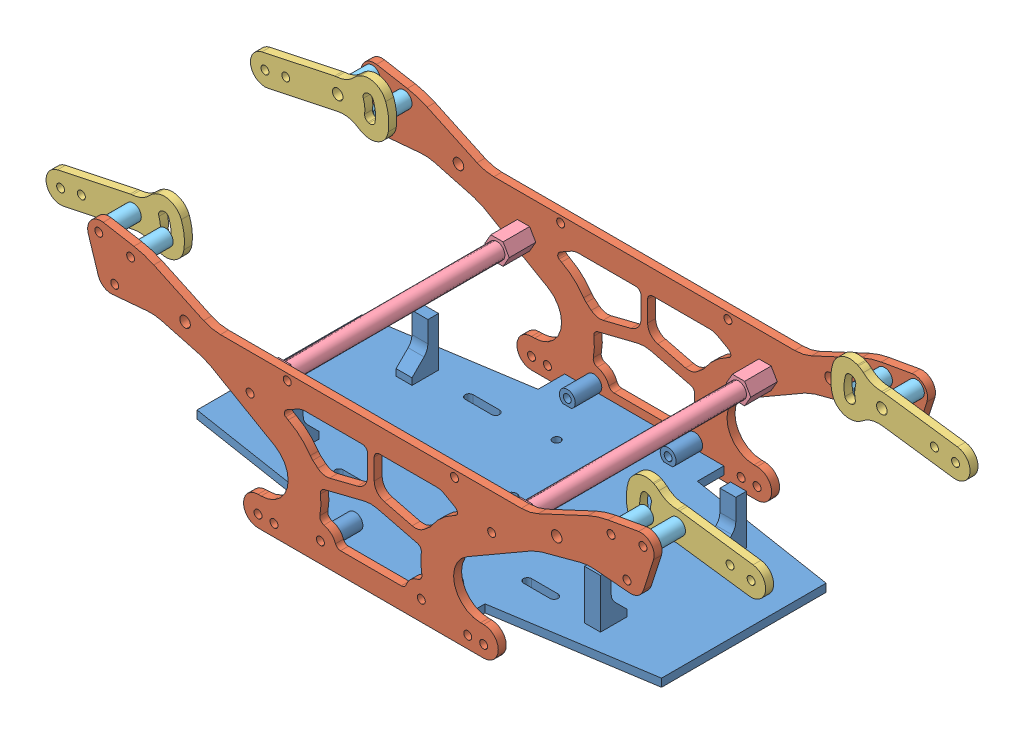
SolidWorks assembly Core, configuration Default. Lengths in mm.
Overall size (273.89 78.88 106.01).
17 component instances, 5 part files, 38 mates.
Components (placement in the parent):
- Chassis_2-1: Chassis_2 [Default] at origin size (175 21.5 100)
- Chassis_1-1: Chassis_1 [Default] at (0 -2 53) x (0 0 -1) z (1 0 0) size (3.01 70.64 213.45)
- Chassis_1-2: Chassis_1 [Default] at (0 -2 -50) x (0 0 -1) z (1 0 0) size (3.01 70.64 213.45)
- Chassis_3-1: Chassis_3 [Default] at (130.2491 60.7601 40) x (0 0 -1) z (0.99104 -0.133567 0) size (3 19.67 52.75)
- Chassis_3-2: Chassis_3 [Default] at (130.2491 60.7601 -37) x (0 0 -1) z (0.99104 -0.133567 0) size (3 19.67 52.75)
- Chassis_3-3: Chassis_3 [Default] at (-129.8911 58.6926 -40) x (0 0 1) z (-0.978254 -0.207408 0) size (3 19.67 52.75)
- Chassis_3-4: Chassis_3 [Default] at (-129.8911 58.6926 37) x (0 0 1) z (-0.978254 -0.207408 0) size (3 19.67 52.75)
- Chassis_4-1: Chassis_4 [Default] at (45.5 40.5 -50) size (9.24 8 100)
- Chassis_4-2: Chassis_4 [Default] at (-45.5 40.5 -50) size (9.24 8 100)
- Chassis_5-1: Chassis_5 [Default] at (90.5 62.3841 40) size (6 6 10)
- Chassis_5-2: Chassis_5 [Default] at (-102.5 64.5 -50) size (6 6 10)
- Chassis_5-3: Chassis_5 [Default] at (-102.5 64.5 40) size (6 6 10)
- Chassis_5-4: Chassis_5 [Default] at (90.5 62.3841 -50) size (6 6 10)
- Chassis_5-5: Chassis_5 [Default] at (102.5 64.5 -50) size (6 6 10)
- Chassis_5-6: Chassis_5 [Default] at (-90.5 62.3841 40) x (0.998337 0.057643 0) z (0 0 1) size (6 6 10)
- Chassis_5-7: Chassis_5 [Default] at (102.5 64.5 40) x (0.975239 -0.221151 0) z (0 0 1) size (6 6 10)
- Chassis_5-8: Chassis_5 [Default] at (-90.5 62.3841 -50) size (6 6 10)
Mates (geometry in assembly coordinates):
- Coincident1: coincident anti-aligned: plane of Chassis_2-1 through (0 3 50) normal (0 0 1); plane of Chassis_1-1 through (0 -2 50) normal (0 0 -1)
- Concentric1: concentric aligned: cylinder of Chassis_2-1 through (19 5.5 40) axis (0 0 1) radius 1.5; cylinder of Chassis_1-1 through (19 5.5 50) axis (0 0 1) radius 1.5
- Concentric2: concentric aligned: cylinder of Chassis_2-1 through (-19 5.5 40) axis (0 0 1) radius 1.5; cylinder of Chassis_1-1 through (-19 5.5 50) axis (0 0 1) radius 1.5
- Coincident2: coincident anti-aligned: plane of Chassis_2-1 through (0 3 -50) normal (0 0 -1); plane of Chassis_1-2 through (0 -2 -50) normal (0 0 1)
- Concentric3: concentric anti-aligned: cylinder of Chassis_2-1 through (-19 5.5 -40) axis (0 0 -1) radius 1.5; cylinder of Chassis_1-2 through (-19 5.5 -53) axis (0 0 1) radius 1.5
- Concentric4: concentric anti-aligned: cylinder of Chassis_2-1 through (19 5.5 -40) axis (0 0 -1) radius 1.5; cylinder of Chassis_1-2 through (19 5.5 -53) axis (0 0 1) radius 1.5
- Concentric5: concentric aligned: circle of Chassis_1-1; cylinder of Chassis_3-1 through (102.5 64.5 37) axis (0 0 1) radius 2
- Distance1: distance = 10 mm anti-aligned: plane of Chassis_3-1 through (130.2491 60.7601 40) normal (0 0 1); plane of Chassis_1-1 through (0 -2 50) normal (0 0 -1)
- Concentric6: concentric aligned: cylinder of Chassis_1-2 through (102.5 64.5 -53) axis (0 0 1) radius 1.5; cylinder of Chassis_3-2 through (102.5 64.5 -40) axis (0 0 1) radius 2
- Distance2: distance = 10 mm anti-aligned: plane of Chassis_3-2 through (130.2491 60.7601 -40) normal (0 0 -1); plane of Chassis_1-2 through (0 -2 -50) normal (0 0 1)
- Parallel1: parallel aligned: plane of Chassis_3-1 through (130.9837 66.2108 37) normal (0.133567 0.99104 0); plane of Chassis_3-2 through (130.9837 66.2108 -40) normal (0.133567 0.99104 0)
- Concentric7: concentric anti-aligned: cylinder of Chassis_1-2 through (-102.5 64.5 -53) axis (0 0 1) radius 1.5; cylinder of Chassis_3-3 through (-102.5 64.5 -37) axis (0 0 -1) radius 2
- Distance3: distance = 10 mm anti-aligned: plane of Chassis_3-3 through (-129.8911 58.6926 -40) normal (0 0 -1); plane of Chassis_1-2 through (0 -2 -50) normal (0 0 1)
- Concentric9: concentric anti-aligned: cylinder of Chassis_1-1 through (-102.5 64.5 50) axis (0 0 1) radius 1.5; cylinder of Chassis_3-4 through (-102.5 64.5 40) axis (0 0 -1) radius 2
- Distance4: distance = 10 mm anti-aligned: plane of Chassis_3-4 through (-129.8911 58.6926 40) normal (0 0 1); plane of Chassis_1-1 through (0 -2 50) normal (0 0 -1)
- Parallel2: parallel aligned: plane of Chassis_3-3 through (-131.0319 64.073 -37) normal (-0.207408 0.978254 0); plane of Chassis_3-4 through (-131.0319 64.073 40) normal (-0.207408 0.978254 0)
- Coincident9: coincident anti-aligned: plane of Chassis_1-2 through (0 -2 -50) normal (0 0 1); plane of Chassis_4-1 through (45.5 40.5 -50) normal (0 0 -1)
- Concentric10: concentric anti-aligned: cylinder of Chassis_1-2 through (45.5 40.5 -53) axis (0 0 1) radius 1.5; cylinder of Chassis_4-1 through (45.5 40.5 50) axis (0 0 -1) radius 1.5
- Parallel3: parallel anti-aligned: plane of Chassis_2-1 through (0 3 0) normal (0 1 0); plane of Chassis_4-1 through (43.1906 36.5 -40) normal (0 -1 0)
- Parallel4: parallel anti-aligned: plane of Chassis_2-1 through (0 3 0) normal (0 1 0); plane of Chassis_4-2 through (-47.8094 36.5 -40) normal (0 -1 0)
- Concentric11: concentric anti-aligned: cylinder of Chassis_1-2 through (-45.5 40.5 -53) axis (0 0 1) radius 1.5; cylinder of Chassis_4-2 through (-45.5 40.5 50) axis (0 0 -1) radius 1.5
- Coincident12: coincident anti-aligned: plane of Chassis_1-2 through (0 -2 -50) normal (0 0 1); plane of Chassis_4-2 through (-45.5 40.5 -50) normal (0 0 -1)
- Concentric12: concentric anti-aligned: cylinder of Chassis_1-1 through (-102.5 64.5 50) axis (0 0 1) radius 1.5; cylinder of Chassis_5-3 through (-102.5 64.5 50) axis (0 0 -1) radius 3
- Coincident13: coincident anti-aligned: plane of Chassis_3-4 through (-129.8911 58.6926 40) normal (0 0 1); plane of Chassis_5-3 through (-102.5 64.5 40) normal (0 0 -1)
- Concentric13: concentric anti-aligned: cylinder of Chassis_1-1 through (90.5 62.3841 50) axis (0 0 1) radius 1.5; cylinder of Chassis_5-1 through (90.5 62.3841 50) axis (0 0 -1) radius 3
- Coincident14: coincident anti-aligned: plane of Chassis_1-1 through (0 -2 50) normal (0 0 -1); plane of Chassis_5-1 through (90.5 62.3841 50) normal (0 0 1)
- Concentric14: concentric anti-aligned: circle of Chassis_3-3; cylinder of Chassis_5-2 through (-102.5 64.5 -40) axis (0 0 -1) radius 3
- Coincident15: coincident anti-aligned: plane of Chassis_3-3 through (-129.8911 58.6926 -40) normal (0 0 -1); plane of Chassis_5-2 through (-102.5 64.5 -40) normal (0 0 1)
- Concentric15: concentric anti-aligned: cylinder of Chassis_1-2 through (90.5 62.3841 -53) axis (0 0 1) radius 1.5; cylinder of Chassis_5-4 through (90.5 62.3841 -40) axis (0 0 -1) radius 3
- Coincident16: coincident anti-aligned: plane of Chassis_3-2 through (130.2491 60.7601 -40) normal (0 0 -1); plane of Chassis_5-4 through (90.5 62.3841 -40) normal (0 0 1)
- Concentric16: concentric anti-aligned: cylinder of Chassis_3-2 through (102.5 64.5 -40) axis (0 0 1) radius 2; cylinder of Chassis_5-5 through (102.5 64.5 -40) axis (0 0 -1) radius 3
- Coincident17: coincident anti-aligned: plane of Chassis_3-2 through (130.2491 60.7601 -40) normal (0 0 -1); plane of Chassis_5-5 through (102.5 64.5 -40) normal (0 0 1)
- Concentric17: concentric anti-aligned: cylinder of Chassis_1-2 through (-90.5 62.3841 -53) axis (0 0 1) radius 1.5; cylinder of Chassis_5-8 through (-90.5 62.3841 -40) axis (0 0 -1) radius 3
- Coincident18: coincident anti-aligned: plane of Chassis_3-3 through (-129.8911 58.6926 -40) normal (0 0 -1); plane of Chassis_5-8 through (-90.5 62.3841 -40) normal (0 0 1)
- Concentric18: concentric anti-aligned: cylinder of Chassis_1-1 through (-90.5 62.3841 50) axis (0 0 1) radius 1.5; cylinder of Chassis_5-6 through (-90.5 62.3841 50) axis (0 0 -1) radius 3
- Coincident19: coincident anti-aligned: plane of Chassis_1-1 through (0 -2 50) normal (0 0 -1); plane of Chassis_5-6 through (-90.5 62.3841 50) normal (0 0 1)
- Concentric19: concentric anti-aligned: cylinder of Chassis_3-1 through (102.5 64.5 37) axis (0 0 1) radius 2; cylinder of Chassis_5-7 through (102.5 64.5 50) axis (0 0 -1) radius 3
- Coincident20: coincident anti-aligned: plane of Chassis_1-1 through (0 -2 50) normal (0 0 -1); plane of Chassis_5-7 through (102.5 64.5 50) normal (0 0 1)
